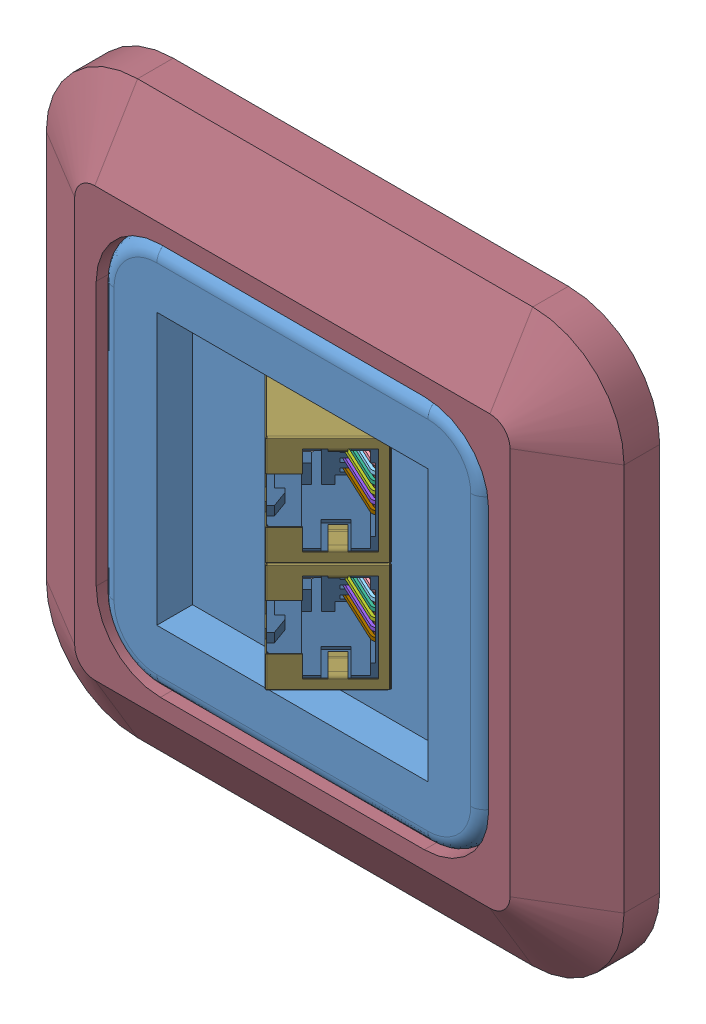
SolidWorks assembly Steckdose_1er-RJ, configuration Standard. Lengths in mm.
Overall size (81 80 25.23).
27 component instances, 13 part files, 3 mates.
Components (placement in the parent):
- Steckdose-RJ45-1: Steckdose-RJ45 [Standard] at (18.9082 -0.7233 10.2377) size (54 54 25.23)
  - Buchse-RJ45-1: Buchse-RJ45 [Standard] at (-88.9836 -48.9043 64.0274) size (54 54 6.5)
  - 65864-1: 65864 [Default] at (-88.8386 -41.2043 53.1274) size (17.49 15.42 25.23)
    - 65864_01-1: 65864_01 [Default] at origin size (9.69 0.75 13.83)
    - 65864_02-1: 65864_02 [Default] at origin size (9.44 0.68 13.83)
    - 65864_03-1: 65864_03 [Default] at origin size (9.69 0.61 13.84)
    - 65864_04-1: 65864_04 [Default] at origin size (9.44 0.54 13.83)
    - 65864_05-1: 65864_05 [Default] at origin size (9.69 0.54 13.82)
    - 65864_06-1: 65864_06 [Default] at origin size (9.44 0.6 13.83)
    - 65864_07-1: 65864_07 [Default] at origin size (9.69 0.68 13.83)
    - 65864_08-1: 65864_08 [Default] at origin size (9.44 0.75 13.83)
    - 65864_09-1: 65864_09 [Default] at origin size (17.11 15.1 23.65)
    - 65864_10-1: 65864_10 [Default] at origin size (6.36 10.31 6.36)
    - 65864_11-1: 65864_11 [Default] at origin size (17.49 15.42 25.23)
  - 65864-2: 65864 [Default] at (-88.8386 -56.6043 53.1274) size (17.49 15.42 25.23)
    - 65864_01-1: 65864_01 [Default] at origin size (9.69 0.75 13.83)
    - 65864_02-1: 65864_02 [Default] at origin size (9.44 0.68 13.83)
    - 65864_03-1: 65864_03 [Default] at origin size (9.69 0.61 13.84)
    - 65864_04-1: 65864_04 [Default] at origin size (9.44 0.54 13.83)
    - 65864_05-1: 65864_05 [Default] at origin size (9.69 0.54 13.82)
    - 65864_06-1: 65864_06 [Default] at origin size (9.44 0.6 13.83)
    - 65864_07-1: 65864_07 [Default] at origin size (9.69 0.68 13.83)
    - 65864_08-1: 65864_08 [Default] at origin size (9.44 0.75 13.83)
    - 65864_09-1: 65864_09 [Default] at origin size (17.11 15.1 23.65)
    - 65864_10-1: 65864_10 [Default] at origin size (6.36 10.31 6.36)
    - 65864_11-1: 65864_11 [Default] at origin size (17.49 15.42 25.23)
- Wandplatte-1: Wandplatte [1er] at (-110.5754 -89.6276 74.2651) size (81 80 11)
Mates (geometry in assembly coordinates):
- Deckungsgleich1: coincident anti-aligned: plane of Steckdose-RJ45-1/Buchse-RJ45-1 through (-89.0754 -68.6276 68.2651) normal (0 0 -1); plane of Wandplatte-1 through (-88.5754 -68.1276 68.2651) normal (0 0 1)
- Abstand1: distance = 0.5 mm anti-aligned: plane of Steckdose-RJ45-1/Buchse-RJ45-1 through (-89.0754 -22.6276 68.2651) normal (0 1 0); plane of Wandplatte-1 through (-88.5754 -22.1276 68.2651) normal (0 -1 0)
- Abstand2: distance = 0.5 mm anti-aligned: plane of Steckdose-RJ45-1/Buchse-RJ45-1 through (-43.0754 -30.6276 68.2651) normal (1 0 0); plane of Wandplatte-1 through (-42.5754 -31.1276 68.2651) normal (-1 0 0)
